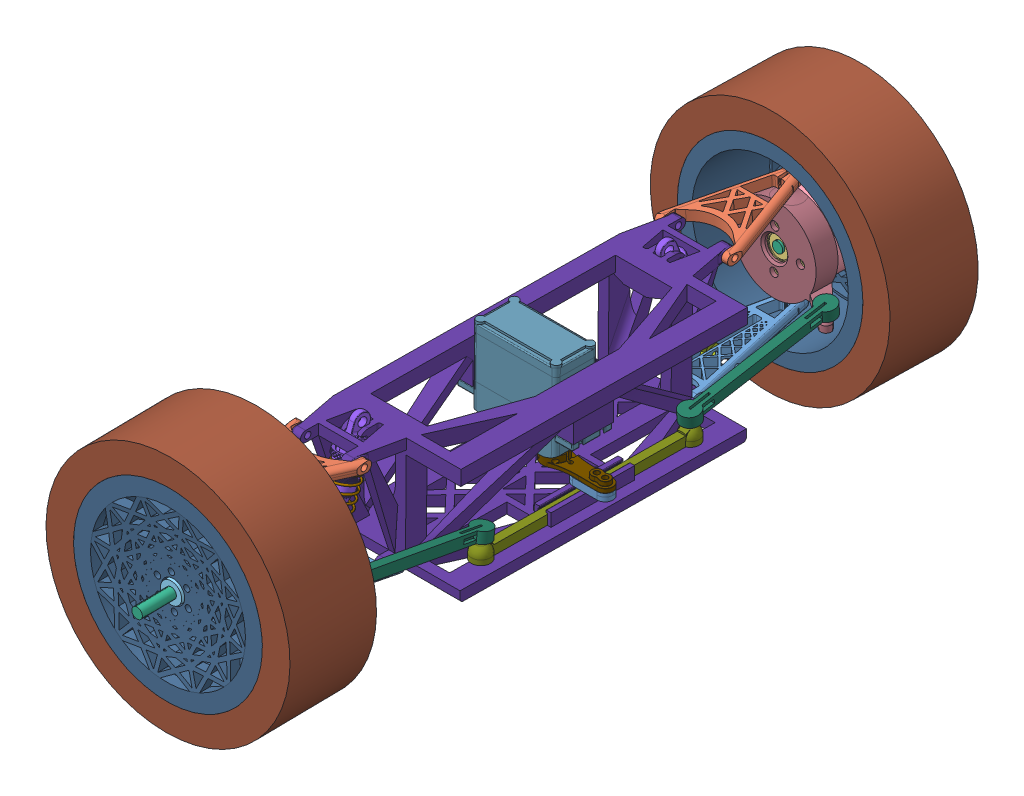
SolidWorks assembly suspension testbed, configuration Default. Lengths in mm.
Overall size (163.07 162.48 361.31).
35 component instances, 19 part files, 46 mates.
Components (placement in the parent):
- lower_control_arm_front-1: lower_control_arm_front [Default] at (37.8305 34.4097 156.0639) x (-1 -0.000948 0.000015) z (-0.000005 0.020378 0.999792) size (37.59 5.03 71.52)
- upper_control_arm_front-1: upper_control_arm_front [Default] at (37.7854 81.9136 152.3027) x (1 0.000948 -0.000015) z (-0.000064 0.083342 0.996521) size (35.03 5.03 51.52)
- d3536-1: d3536 [Default] at (53.6879 75.7463 159.2941) x (-0.999893 0.000187 0.014602) z (-0.000184 -1 0.000177) size (46.45 53.5 46.45)
  - bottom_case-1: bottom_case [Default] at (15.7997 3.4433 17.5887) size (35 8.57 35)
  - middle_case-1: middle_case [Default] at (15.7997 -15.0567 17.5887) x (-0.998365 0 0.05716) z (-0.05716 0 -0.998365) size (35 18 35)
  - top_case-1: top_case [Default] at (15.7997 -15.0567 17.5887) x (-0.907758 0 0.419495) z (0.419495 0 0.907758) size (35 9.5 35)
  - shaft-1: shaft [Default] at (15.7997 -41.0567 17.5887) x (-0.024609 0 -0.999697) z (0.999697 0 -0.024609) size (5 53.5 5)
- coilover-1: coilover [Default] at (18.4437 13.0935 112.358) x (-0.000316 0.347722 0.937598) z (-0.000894 0.937597 -0.347722) size (15.15 15.15 65.67)
  - strut bottom-1: strut bottom [Default] at (8.2738 19.4064 16.0769) size (13 13 37)
  - strut top-1: strut top [Default] at (8.2738 20.4064 60.2501) x (0.996359 -0.085262 0) z (0.085262 0.996359 0) size (14.01 35 14.01)
  - spring-1: spring [Default] at (8.2738 20.4064 29.0769) x (1 0 0) z (0 -1 0) size (13.4 33.17 15.01)
- 8th scale wheel-1: 8th scale wheel [Default] at (38.2233 58.1646 182.5821) x (-0.64022 -0.768133 0.009484) z (-0.014602 -0.000175 -0.999893) size (89 89 42)
- 8th scale tire-1: 8th scale tire [Default] at (37.6538 58.1578 143.5863) x (0.674977 0.737771 -0.009986) z (0.737694 -0.675051 -0.010655) size (115 42 115)
- dside_front_knuckle-1: dside_front_knuckle [Default] at (37.7122 58.1585 147.5858) x (-0.000184 -1 0.000177) z (0.999893 -0.000187 -0.014602) size (55 23.73 55.17)
- lower_control_arm_front-2: lower_control_arm_front [Default] at (37.829 31.8434 -114.8581) x (1 0.000948 -0.000015) z (-0.000017 0.002593 -0.999997) size (37.59 5.03 71.52)
- upper_control_arm_front-2: upper_control_arm_front [Default] at (37.7839 79.4131 -112.0507) x (-1 -0.000948 0.000015) z (-0.000078 0.066603 -0.99778) size (35.03 5.03 51.52)
- pside_front_knuckle-1: pside_front_knuckle [Default] at (37.7832 55.7564 -106.8569) x (0.000673 -0.999805 0.019753) z (0.999993 0.000743 0.003532) size (55 23.73 55.17)
- coilover-2: coilover [Default] at (18.4369 17.2887 -86.8539) x (0.000361 -0.36633 0.930485) z (-0.000877 0.930485 0.36633) size (15.15 15.15 65.67)
  - strut bottom-1: strut bottom [Default] at (8.2738 19.4064 16.0769) size (13 13 37)
  - strut top-1: strut top [Default] at (8.2738 20.4064 60.2501) x (0.996359 -0.085262 0) z (0.085262 0.996359 0) size (14.01 35 14.01)
  - spring-1: spring [Default] at (8.2738 20.4064 29.0769) x (1 0 0) z (0 -1 0) size (13.4 33.17 15.01)
- d3536-2: d3536 [Default] at (22.0141 73.094 -119.201) x (0.999993 0.000743 0.003532) z (0.000673 -0.999805 0.019753) size (46.45 53.5 46.45)
  - bottom_case-1: bottom_case [Default] at (15.7997 3.4433 17.5887) size (35 8.57 35)
  - middle_case-1: middle_case [Default] at (15.7997 -15.0567 17.5887) x (-0.998365 0 0.05716) z (-0.05716 0 -0.998365) size (35 18 35)
  - top_case-1: top_case [Default] at (15.7997 -15.0567 17.5887) x (-0.907758 0 0.419495) z (0.419495 0 0.907758) size (35 9.5 35)
  - shaft-1: shaft [Default] at (15.7997 -41.0567 17.5887) x (-0.024609 0 -0.999697) z (0.999697 0 -0.024609) size (5 53.5 5)
- 8th scale wheel-2: 8th scale wheel [Default] at (37.9073 55.0651 -141.8498) x (0.985279 0.170956 0.000117) z (-0.003546 0.01975 0.999799) size (89 89 42)
- 8th scale tire-2: 8th scale tire [Default] at (37.769 55.8354 -102.8577) x (-0.415707 0.909291 -0.019437) z (-0.909492 -0.415692 0.004986) size (115 42 115)
- LewanSoul LD-20M  Servo 20kg-1: LewanSoul LD-20M  Servo 20kg [Default] at (48.3261 89.6711 20.0348) x (1 0.000948 -0.000015) z (-0.000005 -0.009983 -0.99995) size (55.1 45.65 20.12)
- steering arm link-1: steering arm link [Default] at (71.3331 51.2442 103.3467) x (0.036218 -0.150346 -0.98797) z (-0.998936 -0.033706 -0.031491) size (77 5 9)
- steering arm link-2: steering arm link [Default] at (71.7838 49.6596 -62.8608) x (0.033487 -0.132978 0.990553) z (0.997191 -0.061991 -0.042034) size (77 5 9)
- steering arm center-1: steering arm center [Default] at (72.6804 32.4285 20.4208) x (-0.000005 -0.009983 -0.99995) z (1 0.000948 -0.000015) size (109 12 9)
- front subframe-1: front subframe [Default] at (-3.58 -30.3073 -81.5957) x (1 0.000948 -0.000015) z (0.000005 0.009983 0.99995) size (61.1 55 184.24)
- Servo Mount - Arm Metal Standard-1: Servo Mount - Arm Metal Standard [Défaut] at (58.3211 42.2329 20.5084) x (-0.004502 0.009978 0.99994) z (-0.000948 0.99995 -0.009983) size (12.43 33.73 5.41)
- steering servo attachment-1: steering servo attachment [Default] at (58.3211 42.2329 20.5084) x (0.004502 -0.009978 -0.99994) z (0.000948 -0.99995 0.009983) size (7.5 19.25 3.5)
Mates (geometry in assembly coordinates):
- Concentric1: concentric: sphere of lower_control_arm_front-1; sphere of dside_knuckle_front-1
- Concentric2: concentric: sphere of upper_control_arm_front-1; sphere of dside_knuckle_front-1
- Concentric3: concentric aligned: circle of dside_knuckle_front-1; circle of d3536-1/bottom_case-1
- Coincident4: coincident aligned: circle of dside_knuckle_front-1; circle of d3536-1/bottom_case-1
- Concentric4: concentric aligned: circle of lower_control_arm_front-1; circle of coilover-1/strut bottom-1
- Coincident5: coincident anti-aligned: plane of lower_control_arm_front-1 through (39.8744 -11.798 157.0057) normal (-1 -0.000948 0.000015); plane of coilover-1/strut bottom-1 through (39.8331 31.0644 114.5249) normal (1 0.000948 -0.000015)
- Coincident6: coincident: circle of d3536-1/top_case-1; circle of wheel-1
- Concentric5: concentric anti-aligned: circle of d3536-1/top_case-1; circle of 8th scale wheel-1
- Concentric6: concentric anti-aligned: circle of d3536-1/top_case-1; circle of 8th scale wheel-1
- Coincident7: coincident anti-aligned: plane of d3536-1/top_case-1 through (38.1941 58.1642 180.5823) normal (0.014602 0.000175 0.999893); plane of 8th scale wheel-1 through (38.1941 58.1642 180.5823) normal (-0.014602 -0.000175 -0.999893)
- Coincident8: coincident aligned: circle of 8th scale wheel-1; circle of 8th scale tire-1
- Concentric7: concentric: sphere of lower_control_arm_front-1; sphere of dside_front_knuckle-1
- Concentric8: concentric: sphere of upper_control_arm_front-1; sphere of dside_front_knuckle-1
- Concentric9: concentric aligned: circle of d3536-1/bottom_case-1; circle of dside_front_knuckle-1
- Concentric10: concentric aligned: circle of d3536-1/bottom_case-1; circle of dside_front_knuckle-1
- Coincident11: coincident anti-aligned: plane of d3536-1/bottom_case-1 through (37.7122 58.1585 147.5858) normal (-0.014602 -0.000175 -0.999893); plane of dside_front_knuckle-1 through (37.7122 58.1585 147.5858) normal (0.014602 0.000175 0.999893)
- Concentric11: concentric: sphere of lower_control_arm_front-2; sphere of pside_front_knuckle-1
- Concentric12: concentric: sphere of upper_control_arm_front-2; sphere of pside_front_knuckle-1
- Concentric13: concentric anti-aligned: circle of pside_front_knuckle-1; circle of d3536-2/bottom_case-1
- Concentric14: concentric anti-aligned: circle of pside_front_knuckle-1; circle of d3536-2/bottom_case-1
- Coincident19: coincident anti-aligned: plane of pside_front_knuckle-1 through (37.7832 55.7564 -106.8569) normal (0.003546 -0.01975 -0.999799); plane of d3536-2/bottom_case-1 through (37.7832 55.7564 -106.8569) normal (-0.003546 0.01975 0.999799)
- Concentric15: concentric anti-aligned: circle of lower_control_arm_front-2; circle of coilover-2/strut bottom-1
- Coincident20: coincident anti-aligned: plane of lower_control_arm_front-2 through (39.8728 -14.3738 -114.978) normal (-1 -0.000948 0.000015); plane of coilover-2/strut bottom-1 through (39.8321 29.2374 -73.2662) normal (1 0.000948 -0.000015)
- Concentric16: concentric anti-aligned: circle of d3536-2/top_case-1; circle of 8th scale wheel-2
- Coincident21: coincident aligned: circle of 8th scale wheel-2; circle of 8th scale tire-2
- Concentric17: concentric anti-aligned: circle of d3536-2/top_case-1; circle of 8th scale wheel-2
- Coincident22: coincident anti-aligned: plane of d3536-2/top_case-1 through (37.9002 55.1046 -139.8502) normal (0.003546 -0.01975 -0.999799); plane of 8th scale wheel-2 through (37.9002 55.1046 -139.8502) normal (-0.003546 0.01975 0.999799)
- Concentric20: concentric: sphere of dside_front_knuckle-1; sphere of steering arm link-1
- Concentric21: concentric: sphere of pside_front_knuckle-1; sphere of steering arm link-2
- Concentric22: concentric: sphere of steering arm link-1; sphere of steering arm center-1
- Concentric23: concentric: sphere of steering arm link-2; sphere of steering arm center-1
- Coincident42: coincident anti-aligned: circle of upper_control_arm_front-1; circle of front subframe-1
- Coincident43: coincident aligned: circle of lower_control_arm_front-1; circle of front subframe-1
- Coincident44: coincident anti-aligned: circle of lower_control_arm_front-2; circle of front subframe-1
- Coincident45: coincident aligned: circle of upper_control_arm_front-2; circle of front subframe-1
- Coincident55: coincident anti-aligned: plane of LewanSoul LD-20M  Servo 20kg-1 through (58.3194 44.0328 20.4904) normal (0.000948 -0.99995 0.009983); plane of Servo Mount - Arm Metal Standard-1 through (58.3194 44.0328 20.4904) normal (-0.000948 0.99995 -0.009983)
- Concentric29: concentric aligned: circle of LewanSoul LD-20M  Servo 20kg-1; circle of Servo Mount - Arm Metal Standard-1
- Coincident64: coincident anti-aligned: plane of LewanSoul LD-20M  Servo 20kg-1 through (28.3145 49.0538 10.3899) normal (-1 -0.000948 0.000015); plane of front subframe-1 through (28.4011 -41.1458 79.8438) normal (1 0.000948 -0.000015)
- Coincident65: coincident anti-aligned: plane of LewanSoul LD-20M  Servo 20kg-1 through (23.303 61.2489 15.3184) normal (-0.000948 0.99995 -0.009983); plane of front subframe-1 through (-3.6659 60.2468 -82.4997) normal (0.000948 -0.99995 0.009983)
- Coincident67: coincident aligned: plane of LewanSoul LD-20M  Servo 20kg-1 through (28.303 61.2082 10.7686) normal (-0.000005 -0.009983 -0.99995); plane of front subframe-1 through (-3.6654 61.1779 10.7691) normal (-0.000005 -0.009983 -0.99995)
- Coincident68: coincident anti-aligned: plane of steering arm center-1 through (72.6804 32.4285 20.4208) normal (0.000948 -0.99995 0.009983); plane of front subframe-1 through (28.3309 33.142 96.103) normal (-0.000948 0.99995 -0.009983)
- Coincident69: coincident anti-aligned: plane of steering arm center-1 through (74.6757 37.4302 20.3709) normal (1 0.000948 -0.000015); plane of front subframe-1 through (74.6752 36.4056 -82.2621) normal (-1 -0.000948 0.000015)
- Concentric30: concentric anti-aligned: circle of Servo Mount - Arm Metal Standard-1; circle of steering servo attachment-1
- Concentric31: concentric anti-aligned: circle of Servo Mount - Arm Metal Standard-1; circle of steering servo attachment-1
- Coincident72: coincident anti-aligned: plane of Servo Mount - Arm Metal Standard-1 through (82.3209 42.2568 20.6162) normal (0.000948 -0.99995 0.009983); plane of steering servo attachment-1 through (58.3211 42.2329 20.5084) normal (-0.000948 0.99995 -0.009983)
- Tangent5: tangent anti-aligned: cylinder of steering arm center-1 through (72.6724 40.9281 20.336) axis (0.000948 -0.99995 0.009983) radius 1.5; plane of steering servo attachment-1 through (58.3323 38.7156 18.7934) normal (-0.004502 0.009978 0.99994)
